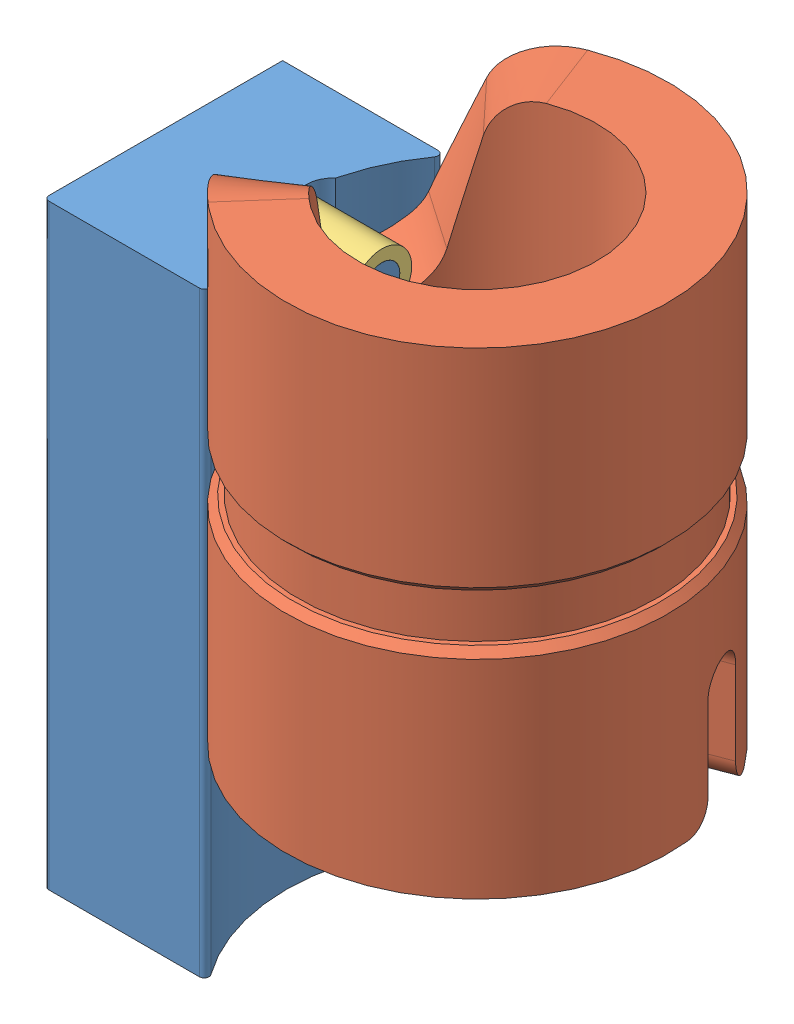
SolidWorks assembly SESTAVA-Výřez, configuration Výchozí. Lengths in mm.
Overall size (234.89 295.12 206.64).
3 component instances, 3 part files, 4 mates.
Components (placement in the parent):
- Pin^SESTAVA-Výřez-1: Pin^SESTAVA-Výřez [Výchozí] at origin size (91.63 250 100) (virtual)
- Valec^SESTAVA-Výřez-1: Valec^SESTAVA-Výřez [Výchozí] at (0 192.9903 0) x (-0.934322 0 0.35643) z (-0.35643 0 -0.934322) size (160 202.13 160.13) (virtual)
- kluzák^SESTAVA-Výřez-1: kluzák^SESTAVA-Výřez [Výchozí] at (-40 240 0) x (0 -0.9988 -0.048983) z (-1 0 0) size (25 25 40) (virtual)
Mates (geometry in assembly coordinates):
- Concentric1: concentric aligned: cylinder of Valec^SESTAVA-Výřez-1 through (0 292.9903 0) axis (0 -1 0) radius 50; cylinder of Pin^SESTAVA-Výřez-1 through (0 250 0) axis (0 -1 0) radius 80
- Concentric2: concentric aligned: cylinder of Pin^SESTAVA-Výřez-1 through (-90 240 0) axis (1 0 0) radius 7.5; cylinder of kluzák^SESTAVA-Výřez-1 through (-80 240 0) axis (1 0 0) radius 7.5
- Coincident1: coincident aligned: plane of Pin^SESTAVA-Výřez-1 through (-40 240 0) normal (1 0 0); plane of kluzák^SESTAVA-Výřez-1 through (-40 240 0) normal (1 0 0)
- PathMate2: path: point of kluzák^SESTAVA-Výřez-1; curve of Valec^SESTAVA-Výřez-1
